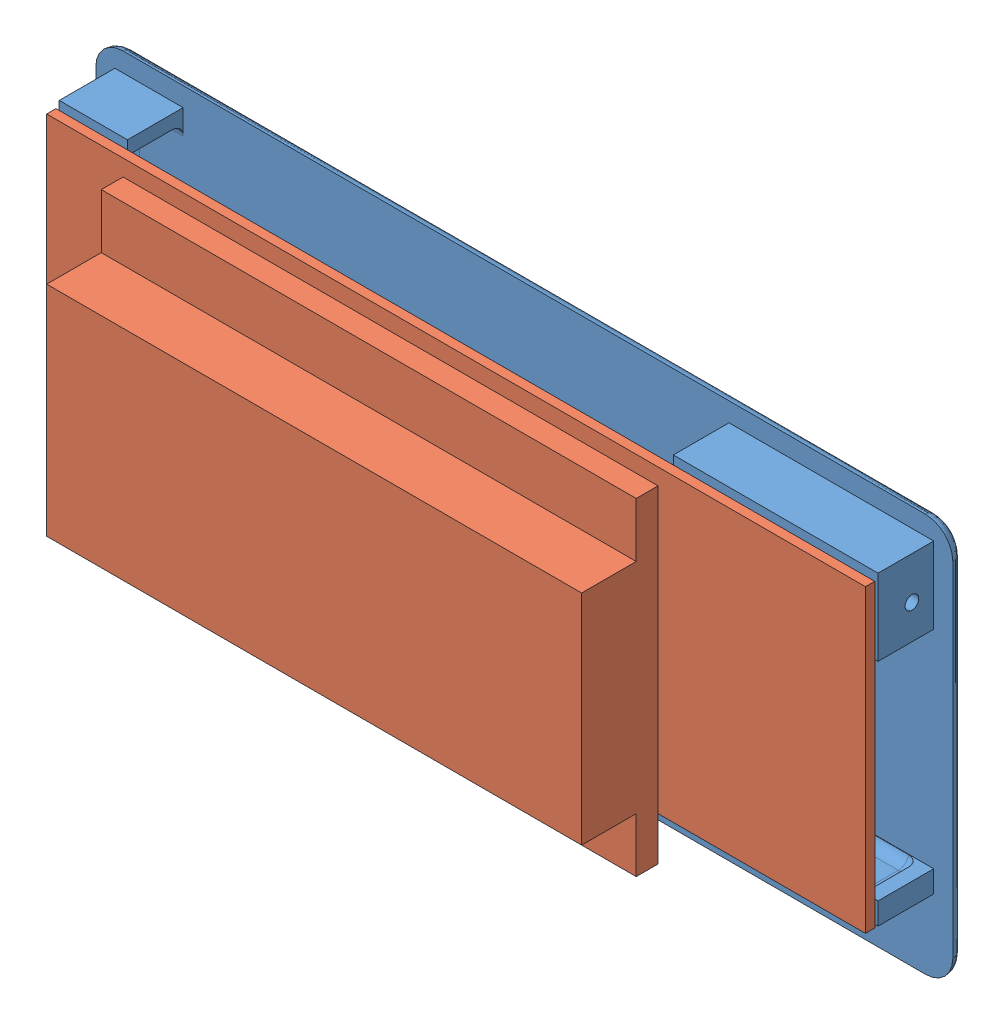
SolidWorks assembly composizione, configuration Default. Lengths in mm.
Overall size (237.29 129.09 28.21).
3 component instances, 3 part files, 4 mates.
Components (placement in the parent):
- frontale-1: frontale [Default] at (178.2952 -16.7641 2) x (-1 0 0) z (0 0 -1) size (158.86 94.86 26) (hidden)
- tappo-1: tappo [Default] at (203.2236 -43.3754 -10) x (-1 0 0) z (0 0 -1) size (157 73 12.41)
- base-1: base [Default] at (177.7952 -17.7641 0.3) size (237.29 129.09 15.7)
Mates (geometry in assembly coordinates):
- Coincidente3: coincident anti-aligned: plane of frontale-1 through (178.2952 -16.7641 -10) normal (0 0 -1); plane of tappo-1 through (203.2236 -43.3754 -10) normal (0 0 1)
- Coincidente5: coincident: plane of frontale-1 through (178.2952 -16.7641 2) normal (0 0 -1); plane of base-1 through (177.7952 -17.7641 2) normal (0 0 1)
- Coincidente6: coincident: line of frontale-1 through (115.7952 -45.2641 2) axis (-1 0 0); line of base-1 through (102.7952 -45.2641 2) axis (1 0 0)
- Coincidente7: coincident anti-aligned: line of frontale-1 through (102.7952 -45.2641 2) axis (0 1 0); line of base-1 through (102.7952 9.7359 2) axis (0 -1 0)
